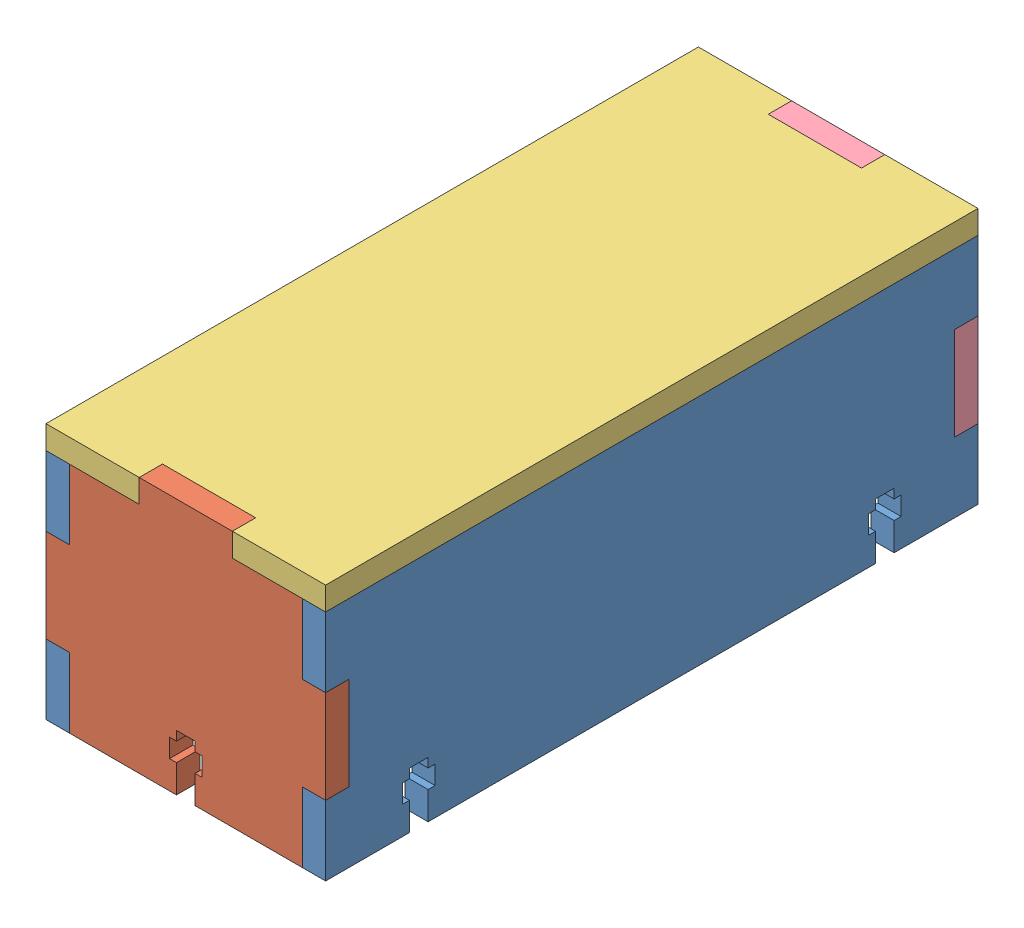
SolidWorks assembly batteryCase, configuration Default. Lengths in mm.
Overall size (60 55 140).
5 component instances, 4 part files, 12 mates.
Components (placement in the parent):
- BatteryCaseSide1-1: BatteryCaseSide1 [Default] at (37.9096 77.0259 111.0197) x (0 -1 0) z (1 0 0) size (50 140 5)
- BatteryCaseSide1-2: BatteryCaseSide1 [Default] at (92.9096 77.0259 111.0197) x (0 -1 0) z (1 0 0) size (50 140 5)
- BatteryCaseSide2-1: BatteryCaseSide2 [Default] at (67.9096 77.0259 176.0197) size (60 55 5)
- BatteryCaseSide3-1: BatteryCaseSide3 [Default] at (72.9096 102.0259 111.0197) x (-1 0 0) z (0 1 0) size (60 140 5)
- BatteryCaseSide4-1: BatteryCaseSide4 [Default] at (69.6609 72.1559 41.0197) size (60 55 5)
Mates (geometry in assembly coordinates):
- Coincident1: coincident aligned: plane of BatteryCaseSide1-1 through (42.9096 102.0259 111.0197) normal (0 1 0); plane of BatteryCaseSide1-2 through (97.9096 102.0259 111.0197) normal (0 1 0)
- Coincident2: coincident aligned: plane of BatteryCaseSide1-1 through (42.9096 52.0259 111.0197) normal (0 -1 0); plane of BatteryCaseSide2-1 through (42.9096 52.0259 181.0197) normal (0 -1 0)
- Coincident3: coincident aligned: plane of BatteryCaseSide1-1 through (37.9096 77.0259 111.0197) normal (-1 0 0); plane of BatteryCaseSide2-1 through (37.9096 67.0259 181.0197) normal (-1 0 0)
- Coincident4: coincident aligned: plane of BatteryCaseSide1-1 through (42.9096 77.0259 181.0197) normal (0 0 1); plane of BatteryCaseSide2-1 through (67.9096 77.0259 181.0197) normal (0 0 1)
- Coincident6: coincident aligned: plane of BatteryCaseSide1-2 through (97.9096 77.0259 181.0197) normal (0 0 1); plane of BatteryCaseSide2-1 through (67.9096 77.0259 181.0197) normal (0 0 1)
- Coincident7: coincident aligned: plane of BatteryCaseSide1-2 through (97.9096 77.0259 111.0197) normal (1 0 0); plane of BatteryCaseSide2-1 through (97.9096 87.0259 181.0197) normal (1 0 0)
- Coincident8: coincident anti-aligned: plane of BatteryCaseSide1-1 through (42.9096 102.0259 111.0197) normal (0 1 0); plane of BatteryCaseSide3-1 through (72.9096 102.0259 111.0197) normal (0 -1 0)
- Coincident9: coincident anti-aligned: plane of BatteryCaseSide2-1 through (67.9096 77.0259 176.0197) normal (0 0 -1); plane of BatteryCaseSide3-1 through (72.9096 107.0259 176.0197) normal (0 0 1)
- Coincident10: coincident aligned: plane of BatteryCaseSide1-1 through (37.9096 77.0259 111.0197) normal (-1 0 0); plane of BatteryCaseSide3-1 through (37.9096 107.0259 111.0197) normal (-1 0 0)
- Coincident11: coincident anti-aligned: plane of BatteryCaseSide1-1 through (42.9096 77.0259 46.0197) normal (0 0 -1); plane of BatteryCaseSide4-1 through (69.6609 72.1559 46.0197) normal (0 0 1)
- Coincident12: coincident aligned: plane of BatteryCaseSide3-1 through (72.9096 107.0259 111.0197) normal (0 1 0); plane of BatteryCaseSide4-1 through (57.9096 107.0259 46.0197) normal (0 1 0)
- Coincident13: coincident aligned: plane of BatteryCaseSide1-2 through (97.9096 77.0259 111.0197) normal (1 0 0); plane of BatteryCaseSide4-1 through (97.9096 87.0259 46.0197) normal (1 0 0)
